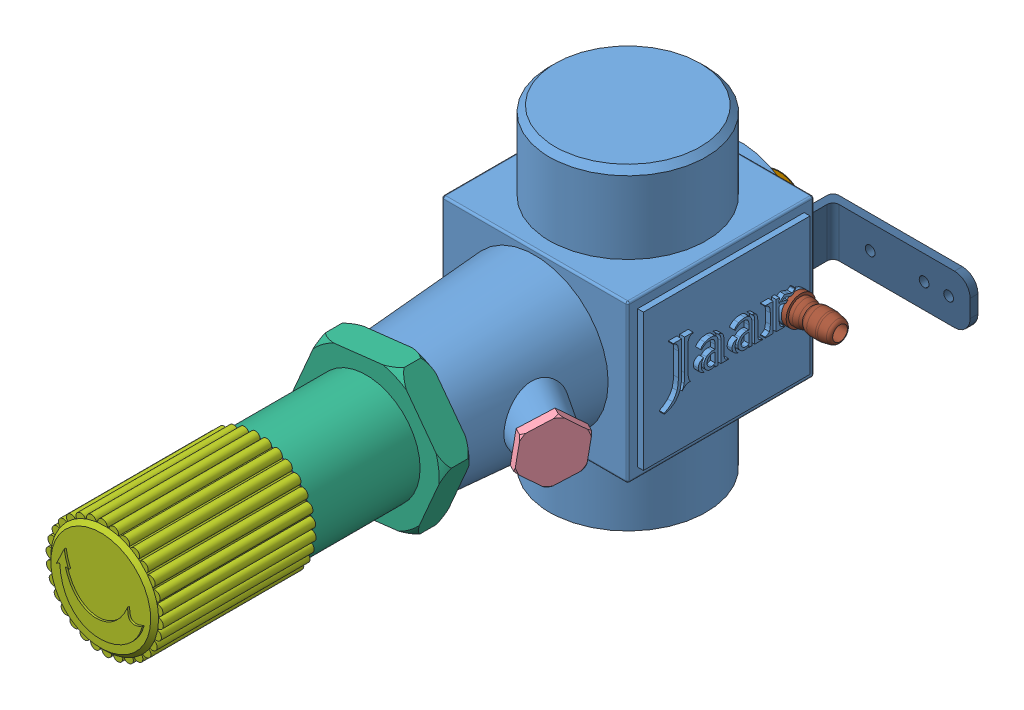
SolidWorks assembly Carburetor, configuration Default. Lengths in mm.
Overall size (14.97 16 35.15).
11 component instances, 11 part files, 22 mates.
Components (placement in the parent):
- Carburetor-1: Carburetor [Default] at (7.8003 6.9699 14.4274) size (10.78 16 17.63)
- Gasket-4-1: Gasket-4 [Default] at (7.8003 14.9699 26.1774) x (0.999785 0.020737 0) z (0 0 1) size (6.52 6.52 0.1)
- Valve-1: Valve [Default] at (7.8003 14.9699 20.0774) x (-0.061878 0.998084 0) z (0 0 -1) size (2.55 2.55 6)
- Wint-1-1: Wint-1 [Default] at (12.7981 14.9699 23.4423) x (-0.456061 0 0.889948) z (-0.889948 0 -0.456061) size (3.08 3.18 4.55)
- Gasket-5-1: Gasket-5 [Default] at (12.7313 14.9699 23.4081) x (0.456061 0 -0.889948) z (0.889948 0 0.456061) size (2.5 2.5 0.07)
- Neadle-1: Neadle [Default] at (7.8003 14.9699 23.2774) size (8.13 7.87 10.24)
- Cone-4: Cone [Default] at (7.8003 14.9699 33.3274) x (-0.996519 -0.083365 0) z (0 0 -1) size (5.99 5.99 14.1)
- Gasket-6-1: Gasket-6 [Default] at (7.8003 14.9699 33.2774) x (0.994998 -0.099895 0) z (0 0 1) size (5.5 5.5 0.05)
- Roll-2: Roll [Default] at (7.8003 14.9699 19.0774) x (0.999932 0.011625 0) z (0 0 -1) size (6 6 12.59)
- Hook-1: Hook [Default] at (7.0058 16.4859 8.6774) x (0 -1 0) z (0 0 -1) size (3.5 11.47 2.4)
- Part7-1: Part7 [Default] at (13.0503 14.9699 11.0942) x (0 0 1) z (-1 0 0) size (1.5 1.5 3.85)
Mates (geometry in assembly coordinates):
- Concentric2: concentric: circle of Carburetor-1; circle of Gasket-4-1
- Distance2: distance = 0 mm: plane of Gasket-4-1 through (7.8003 14.9699 26.1774) normal (0 0 -1); plane of Carburetor-1 through (7.8003 14.9699 26.1774) normal (0 0 1)
- Concentric3: concentric: circle of Gasket-4-1; cylinder of Valve-1 through (7.8003 14.9699 23.0774) axis (0 0 -1) radius 1
- Distance3: distance = 0 mm: plane of Valve-1 through (7.8003 14.9699 21.0774) normal (0 0 -1); plane of Carburetor-1 through (7.8003 14.9699 21.0774) normal (0 0 1)
- Concentric4: concentric: cylinder of Carburetor-1 through (8.2816 14.9699 21.1278) axis (0.889948 0 0.456061) radius 0.375; cylinder of Wint-1-1 through (9.2383 14.9699 21.618) axis (0.889948 0 0.456061) radius 0.375
- Parallel1: parallel: plane of Carburetor-1 through (12.7313 14.9699 23.4081) normal (0.889948 0 0.456061); plane of Gasket-5-1 through (12.7981 14.9699 23.4423) normal (0.889948 0 0.456061)
- Distance4: distance = 0 mm: plane of Gasket-5-1 through (12.7313 14.9699 23.4081) normal (-0.889948 0 -0.456061); plane of Carburetor-1 through (12.7313 14.9699 23.4081) normal (0.889948 0 0.456061)
- Concentric5: concentric: circle of Carburetor-1; circle of Gasket-5-1
- Distance5: distance = 0 mm: plane of Wint-1-1 through (12.7981 14.9699 23.4423) normal (-0.889948 0 -0.456061); plane of Gasket-5-1 through (12.7981 14.9699 23.4423) normal (0.889948 0 0.456061)
- Concentric6: concentric: circle of Carburetor-1; circle of Neadle-1
- Distance6: distance = 0 mm: plane of Neadle-1 through (7.8003 14.9699 26.2774) normal (0 0 -1); plane of Gasket-4-1 through (7.8003 14.9699 26.2774) normal (0 0 1)
- Concentric10: concentric: cylinder of Neadle-1 through (7.8003 14.9699 29.2774) axis (0 0 1) radius 2.25; cylinder of Cone-4 through (7.8003 14.9699 29.3274) axis (0 0 1) radius 2.25
- Concentric11: concentric: circle of Neadle-1; circle of Gasket-6-1
- Distance10: distance = 0 mm: plane of Gasket-6-1 through (7.8003 14.9699 33.2774) normal (0 0 -1); plane of Neadle-1 through (7.8003 14.9699 33.2774) normal (0 0 1)
- Distance11: distance = 0 mm: plane of Cone-4 through (7.8003 14.9699 33.3274) normal (0 0 -1); plane of Gasket-6-1 through (7.8003 14.9699 33.3274) normal (0 0 1)
- Concentric12: concentric: circle of Carburetor-1; cylinder of Roll-2 through (7.8003 14.9699 8.6774) axis (0 0 1) radius 3
- Distance12: distance = 0 mm: plane of Roll-2 through (7.8003 14.9699 8.6774) normal (0 0 -1); plane of Carburetor-1 through (7.8003 14.9699 8.6774) normal (0 0 -1)
- Concentric13: concentric: circle of Roll-2; circle of Hook-1
- Distance13: distance = 0 mm: plane of Hook-1 through (7.8003 14.9699 8.6774) normal (0 0 1); plane of Carburetor-1 through (7.8003 14.9699 8.6774) normal (0 0 -1)
- Parallel2: parallel: plane of Roll-2 through (7.0388 15.9611 13.336) normal (-0.999932 -0.011625 0); plane of Hook-1 through (7.062 13.9613 8.2774) normal (0.999932 0.011625 0)
- Concentric14: concentric: circle of Carburetor-1; circle of Part7-1
- Distance14: distance = 0 mm: plane of Part7-1 through (13.0503 14.9699 11.0942) normal (-1 0 0); plane of Carburetor-1 through (13.0503 14.9699 11.0942) normal (1 0 0)
